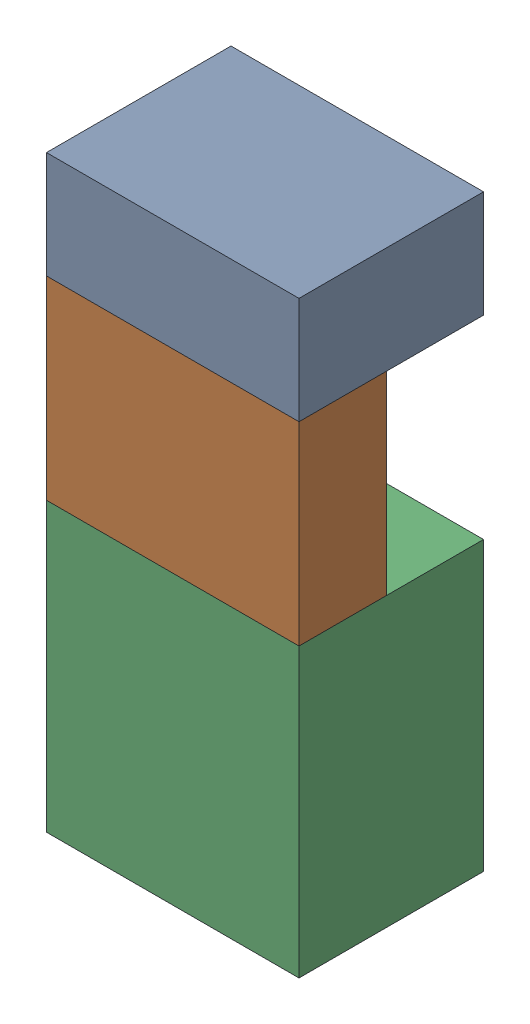
SolidWorks assembly SUP_K14, configuration Default. Lengths in mm.
Overall size (13 30.3 9.5).
6 component instances, 3 part files, 0 mates.
Components (placement in the parent):
- 1151724928-1: 1151724928 [Default] at (210.185 41.975 0) size (13 5.5 9.5)
  - Extruded_2-1: Extruded_2 [Default] at origin size (13 5.5 9.5)
- 1151725064-1: 1151725064 [Default] at (210.185 34.225 5) size (13 10 4.5)
  - Extruded_3-1: Extruded_3 [Default] at origin size (13 10 4.5)
- 1151724792-1: 1151724792 [Default] at (210.185 21.825 0) size (13 14.8 9.5)
  - Extruded_4-1: Extruded_4 [Default] at origin size (13 14.8 9.5)
